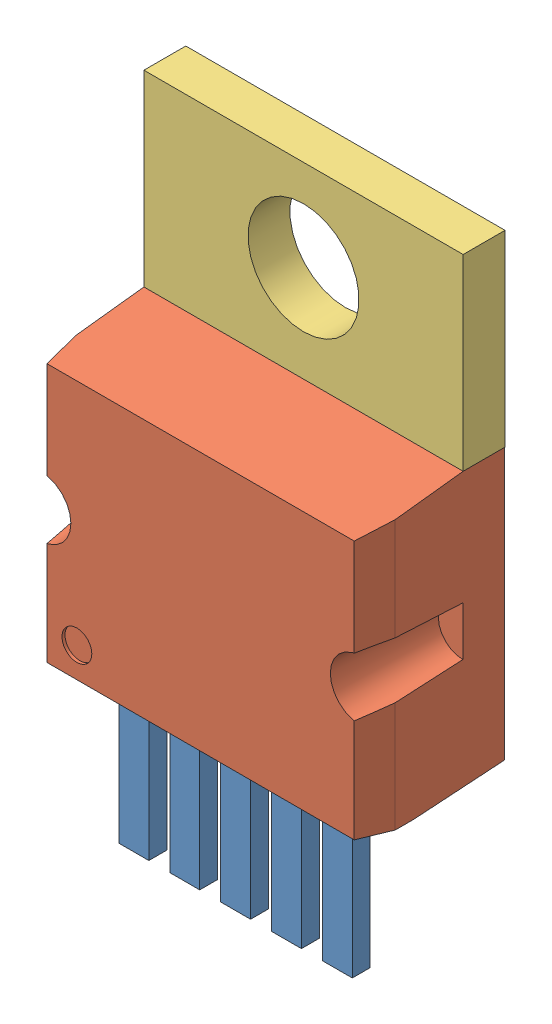
SolidWorks assembly TO220-5-Standing, configuration Default. Lengths in mm.
Overall size (10.67 20.53 4.84).
7 component instances, 3 part files, 9 mates.
Components (placement in the parent):
- P-1: P [Default] at (0 0.025 0) x (-1 0 0) z (0 -1 0) size (1 0.6 5)
- P-6: P [Default] at (1.7 0.025 0) x (-1 0 0) z (0 -1 0) size (1 0.6 5)
- P-7: P [Default] at (3.4 0.025 0) x (-1 0 0) z (0 -1 0) size (1 0.6 5)
- P-8: P [Default] at (-1.7 0.025 0) x (-1 0 0) z (0 -1 0) size (1 0.6 5)
- P-9: P [Default] at (-3.4 0.025 0) x (-1 0 0) z (0 -1 0) size (1 0.6 5)
- Body-2: Body [Default] at (0 7.15 -3.36) x (1 0 0) z (0 -1 0) size (10.67 4.83 9.25)
- EP-2: EP [Default] at (0 15 -3.37) x (1 0 0) z (0 -1 0) size (10.67 1.4 12.88)
Mates (geometry in assembly coordinates):
- Coincident23: coincident anti-aligned: plane of P-1 through (0 0.025 0) normal (0 0 -1); plane of assembly through (0 0 0) normal (0 0 1)
- Coincident24: coincident anti-aligned: plane of P-1 through (0 0.025 0) normal (-1 0 0); plane of assembly through (0 0 0) normal (1 0 0)
- Distance3: distance = 2.475 mm: plane of assembly through (0 0 0) normal (0 1 0); plane of assembly; plane of P-1 through (0.5 -2.475 -0.3) normal (0 -1 0)
- Coincident26: coincident: plane of P-1 through (0.5 2.525 -0.3) normal (0 1 0); plane of Body-2 through (-5.335 2.525 1.47) normal (0 -1 0)
- Coincident27: coincident: plane of P-1 through (0 0.025 0) normal (-1 0 0); plane of Body-2 through (0 7.15 -3.36) normal (1 0 0)
- Coincident28: coincident anti-aligned: line of P-1 through (-0.5 2.525 0.3) axis (1 0 0); line of Body-2 through (5.335 2.525 0.3) axis (-1 0 0)
- Distance4: distance = 0.01 mm: plane of EP-2 through (0 15 -3.37) normal (0 0 -1); plane of Body-2 through (0 7.15 -3.36) normal (0 0 -1)
- Coincident30: coincident: plane of Body-2 through (0 7.15 -3.36) normal (1 0 0); plane of EP-2 through (0 15 -3.37) normal (1 0 0)
- Coincident31: coincident anti-aligned: plane of Body-2 through (-5.335 11.775 1.47) normal (0 1 0); plane of EP-2 through (-5.335 11.775 -3.37) normal (0 -1 0)
